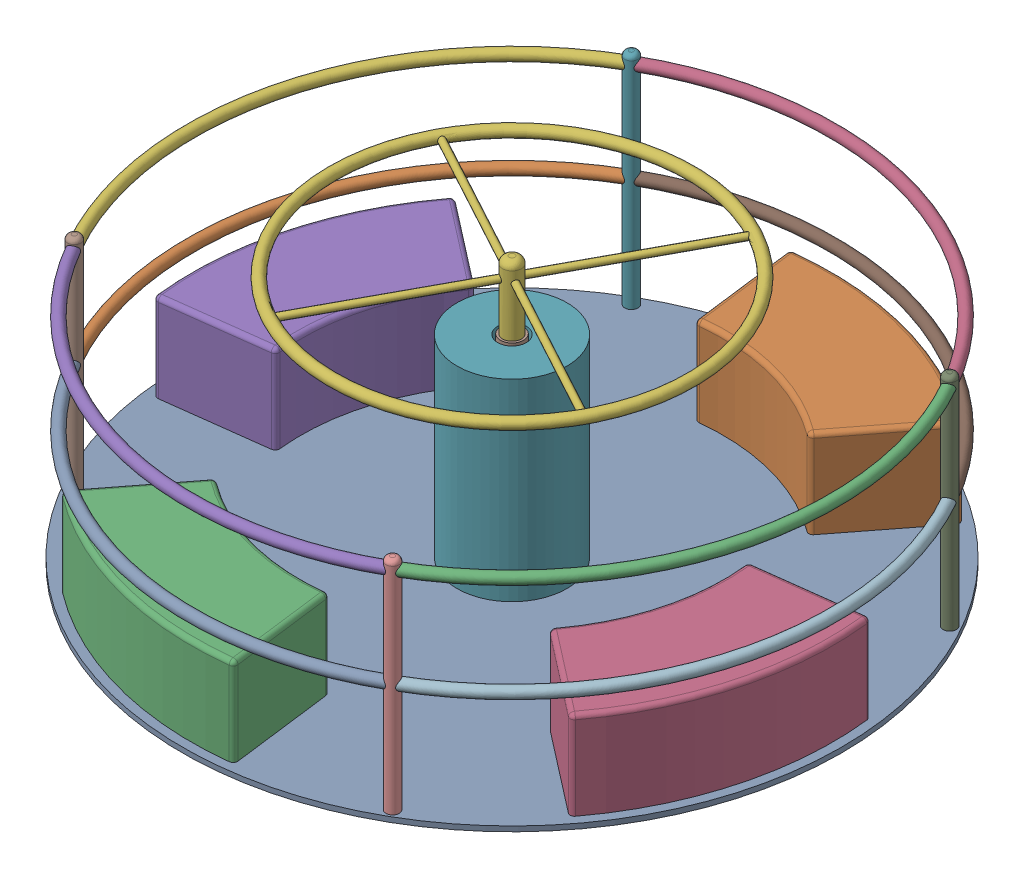
SolidWorks assembly test, configuration Default. Lengths in mm.
Overall size (4093.1 1218 4093.1).
21 component instances, 8 part files, 39 mates.
Components (placement in the parent):
- Baseplate-1: Baseplate [Default] at (168.2415 11.5 2230.1643) x (0.868265 0 -0.4961) z (0.4961 0 0.868265) size (3000 23 3000)
- Seat Block-1: Seat Block [Default] at (168.2415 23 2230.1643) x (0.992022 0 -0.126066) z (0.126066 0 0.992022) size (1023.99 400 772.9)
- Seat Block-2: Seat Block [Default] at (168.2415 23 2230.1643) x (-0.992022 0 0.126066) z (-0.126066 0 -0.992022) size (1023.99 400 772.9)
- Seat Block-3: Seat Block [Default] at (168.2415 23 2230.1643) x (0.126066 0 0.992022) z (-0.992022 0 0.126066) size (1023.99 400 772.9)
- Seat Block-4: Seat Block [Default] at (168.2415 23 2230.1643) x (-0.126066 0 -0.992022) z (0.992022 0 -0.126066) size (1023.99 400 772.9)
- Shaft-1: Shaft [Default] at (168.2415 243 2230.1643) x (-0.476393 0 0.879233) z (-0.879233 0 -0.476393) size (1680 357 1680)
- Vertical Bar-1: Vertical Bar [Default] at (-556.0644 23 962.4968) x (-0.4961 0 -0.868265) z (0.868265 0 -0.4961) size (60 1000 60)
- Vertical Bar-2: Vertical Bar [Default] at (-1099.4259 23 2954.4703) x (0.868265 0 -0.4961) z (0.4961 0 0.868265) size (60 1000 60)
- Vertical Bar-3: Vertical Bar [Default] at (1435.909 23 1505.8584) x (0.868265 0 -0.4961) z (0.4961 0 0.868265) size (60 1000 60)
- Vertical Bar-4: Vertical Bar [Default] at (892.5475 23 3497.8318) x (-0.4961 0 -0.868265) z (0.868265 0 -0.4961) size (60 1000 60)
- Horizontal Bar-3: Horizontal Bar [Default] at (168.2415 523 2230.1643) x (0.868265 0 -0.4961) z (0.4961 0 0.868265) size (1485 50 1485)
- Horizontal Bar-4: Horizontal Bar [Default] at (168.2415 523 2230.1643) x (0.4961 0 0.868265) z (-0.868265 0 0.4961) size (1485 50 1485)
- Horizontal Bar-5: Horizontal Bar [Default] at (168.2415 523 2230.1643) x (0.4961 0 0.868265) z (0.868265 0 -0.4961) size (1485 50 1485)
- Horizontal Bar-6: Horizontal Bar [Default] at (168.2415 523 2230.1643) x (-0.868265 0 0.4961) z (0.4961 0 0.868265) size (1485 50 1485)
- Horizontal Bar-7: Horizontal Bar [Default] at (168.2415 973 2230.1643) x (0.4961 0 0.868265) z (-0.868265 0 0.4961) size (1485 50 1485)
- Horizontal Bar-8: Horizontal Bar [Default] at (168.2415 973 2230.1643) x (0.868265 0 -0.4961) z (0.4961 0 0.868265) size (1485 50 1485)
- Horizontal Bar-9: Horizontal Bar [Default] at (168.2415 973 2230.1643) x (-0.868265 0 0.4961) z (-0.4961 0 -0.868265) size (1485 50 1485)
- Horizontal Bar-10: Horizontal Bar [Default] at (168.2415 973 2230.1643) x (-0.4961 0 -0.868265) z (0.868265 0 -0.4961) size (1485 50 1485)
- hole-1: hole [Default] at (168.2415 0 2230.1643) size (500 900 500)
- axel to gearbox-1: axel to gearbox [Default] at (168.2415 613.5 2230.1643) x (0.81567 0 0.578518) z (-0.578518 0 0.81567) size (241.28 533 230)
- bottom-1: bottom [Default] at (168.2415 370 2230.1643) x (-0.967903 0 -0.251324) z (-0.251324 0 0.967903) size (220 378 220)
Mates (geometry in assembly coordinates):
- Coincident2: coincident aligned: circle of Baseplate-1; circle of Seat Block-4
- Coincident4: coincident aligned: line of Baseplate-1 through (168.2415 23 2230.1643) axis (-0.790607 0 -0.612323); line of Seat Block-4 through (-606.3923 23 1630.2124) axis (-0.790607 0 -0.612323)
- Coincident5: coincident aligned: circle of Baseplate-1; circle of Seat Block-2
- Coincident6: coincident aligned: line of Baseplate-1 through (168.2415 23 2230.1643) axis (-0.612323 0 0.790607); line of Seat Block-2 through (-431.7104 23 3004.7982) axis (-0.612323 0 0.790607)
- Coincident7: coincident aligned: circle of Baseplate-1; circle of Seat Block-1
- Coincident8: coincident aligned: line of Baseplate-1 through (168.2415 23 2230.1643) axis (0.612323 0 -0.790607); line of Seat Block-1 through (768.1935 23 1455.5304) axis (0.612323 0 -0.790607)
- Coincident9: coincident aligned: line of Baseplate-1 through (168.2415 23 2230.1643) axis (0.790607 0 0.612323); line of Seat Block-3 through (942.8754 23 2830.1163) axis (0.790607 0 0.612323)
- Coincident10: coincident anti-aligned: circle of Baseplate-1; circle of Seat Block-3
- Coincident14: coincident aligned: circle of Baseplate-1; circle of Vertical Bar-1
- Coincident15: coincident aligned: circle of Baseplate-1; circle of Vertical Bar-3
- Coincident16: coincident aligned: circle of Baseplate-1; circle of Vertical Bar-4
- Coincident17: coincident aligned: circle of Baseplate-1; circle of Vertical Bar-2
- Coincident29: coincident aligned: circle of Vertical Bar-1; circle of Horizontal Bar-3
- Coincident37: coincident aligned: circle of Vertical Bar-3; circle of Horizontal Bar-3
- Coincident36: coincident aligned: circle of Vertical Bar-3; circle of Horizontal Bar-4
- Coincident38: coincident anti-aligned: circle of Vertical Bar-4; circle of Horizontal Bar-4
- Coincident39: coincident aligned: circle of Vertical Bar-4; circle of Horizontal Bar-5
- Coincident46: coincident aligned: circle of Vertical Bar-2; circle of Horizontal Bar-5
- Coincident47: coincident aligned: circle of Vertical Bar-2; circle of Horizontal Bar-6
- Coincident49: coincident anti-aligned: circle of Vertical Bar-1; circle of Horizontal Bar-6
- Coincident50: coincident anti-aligned: circle of Vertical Bar-4; circle of Horizontal Bar-7
- Coincident51: coincident aligned: circle of Vertical Bar-3; circle of Horizontal Bar-7
- Coincident52: coincident aligned: circle of Vertical Bar-3; circle of Horizontal Bar-8
- Coincident54: coincident aligned: circle of Vertical Bar-1; circle of Horizontal Bar-8
- Coincident55: coincident aligned: circle of Vertical Bar-1; circle of Horizontal Bar-10
- Coincident56: coincident anti-aligned: circle of Vertical Bar-2; circle of Horizontal Bar-10
- Coincident57: coincident anti-aligned: circle of Vertical Bar-2; circle of Horizontal Bar-9
- Coincident58: coincident anti-aligned: circle of Vertical Bar-4; circle of Horizontal Bar-9
- Coincident59: coincident anti-aligned: circle of hole-1; circle of 2349K758_Permanently Lubricated Ball Bearing-1
- Concentric2: concentric anti-aligned: cylinder of axel to gearbox-1 through (168.2415 843 2230.1643) axis (0 -1 0) radius 16; cylinder of planetary_gearbox_bdb_300_-_ratio_4-1/planetary_gearbox_bdb_300_-_ratio_4_04-1 through (-552.6002 263.9124 4440.8424) axis (0 1 0) radius 16
- Coincident60: coincident anti-aligned: plane of axel to gearbox-1 through (168.2415 843 2230.1643) normal (0 -1 0); plane of planetary_gearbox_bdb_300_-_ratio_4-1/planetary_gearbox_bdb_300_-_ratio_4_05-1 through (-643.6802 319.4124 4349.7624) normal (0 1 0)
- Coincident61: coincident anti-aligned: circle of Baseplate-1; circle of hole-1
- Coincident62: coincident anti-aligned: plane of hole-1 through (168.2415 0 2230.1643) normal (0 -1 0)
- Distance1: distance = 190 mm anti-aligned: plane of hole-1 through (168.2415 800 2230.1643) normal (0 -1 0); plane of axel to gearbox-1 through (168.2415 610 2230.1643) normal (0 1 0)
- Concentric4: concentric anti-aligned: cylinder of hole-1 through (168.2415 800 2230.1643) axis (0 -1 0) radius 200; cylinder of axel to gearbox-1 through (168.2415 370 2230.1643) axis (0 1 0) radius 115
- Coincident65: coincident anti-aligned: plane of Shaft-1 through (168.2415 853 2230.1643) normal (0 -1 0); plane of axel to gearbox-1 through (168.2415 853 2230.1643) normal (0 1 0)
- Concentric5: concentric aligned: cylinder of Shaft-1 through (168.2415 53 2230.1643) axis (0 1 0) radius 42.5; cylinder of axel to gearbox-1 through (168.2415 853 2230.1643) axis (0 1 0) radius 42.5
- Concentric6: concentric aligned: cylinder of hole-1 through (168.2415 -456 2230.1643) axis (0 1 0) radius 65; cylinder of bottom-1 through (168.2415 92 2230.1643) axis (0 1 0) radius 110
- Coincident67: coincident anti-aligned: circle of axel to gearbox-1; plane of bottom-1 through (168.2415 370 2230.1643) normal (0 1 0)
